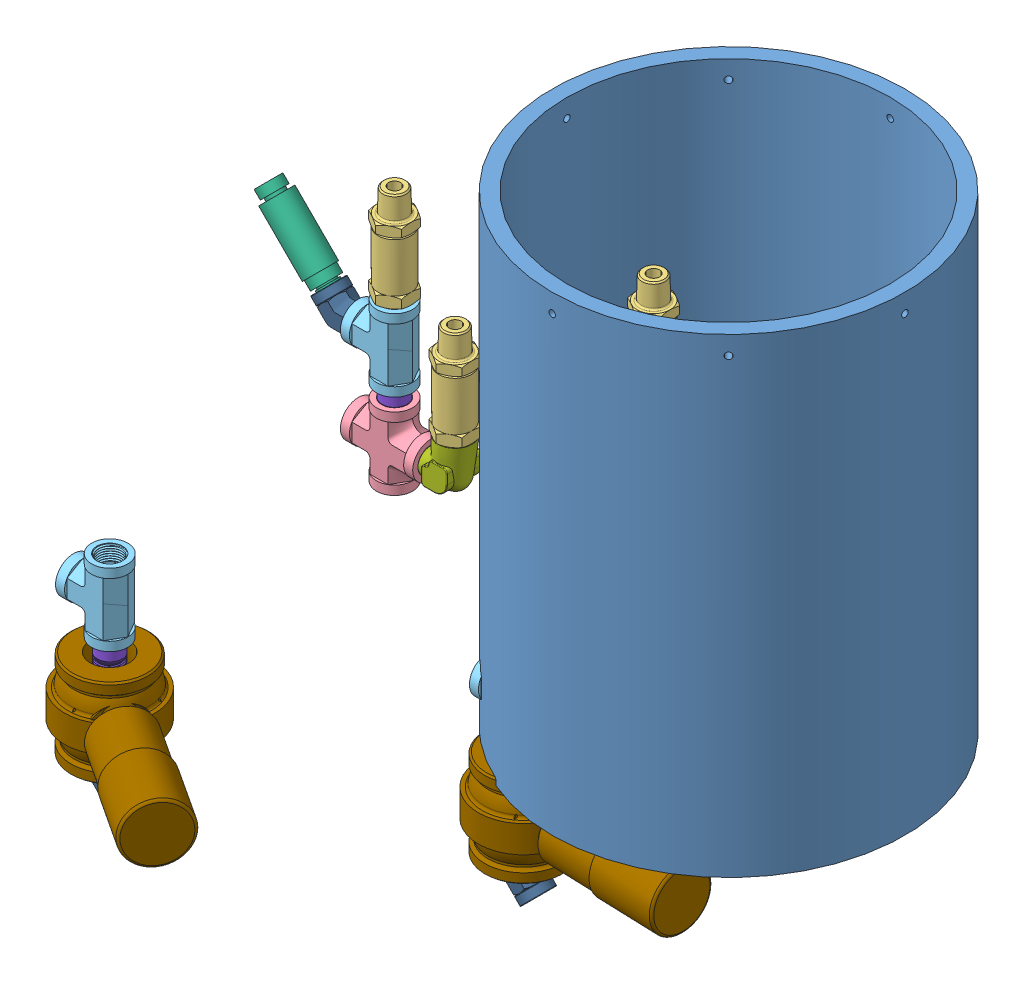
SolidWorks assembly FinCanAssembly, configuration Default. Lengths in mm.
Overall size (594.72 511.85 548.05).
27 component instances, 10 part files, 43 mates.
Components (placement in the parent):
- 000070-R03_FIN_CAN_AF-1: 000070-R03_FIN_CAN_AF [Default] at (23.1188 -196.0045 -17.088) size (304.8 406.4 304.8)
- launch_rail_lugs-1: launch_rail_lugs [Default] at (-92.4476 -84.8795 -132.6545) x (-0.707107 0 0.707107) z (-0.707107 0 -0.707107) size (76.2 32.2 34.22)
- TIN20021-1: TIN20021 [Default] at (7.6331 145.2519 32.2173) x (0 -1 0) z (0 0 1) size (102.11 28.58 33)
- TIN20021-2: TIN20021 [Default] at (-301.1748 13.7827 -52.7696) x (0 -1 0) z (0 0 1) size (102.11 28.58 33)
- 51205K175_EXTREME-PRESSURE 316 SS THREADED PIPE FITTING-1: 51205K175_EXTREME-PRESSURE 316 SS THREADED PIPE FITTING [51205K175] at (7.6331 -24.0899 32.2173) size (63.86 63.86 31.16)
- 51205K175_EXTREME-PRESSURE 316 SS THREADED PIPE FITTING-2: 51205K175_EXTREME-PRESSURE 316 SS THREADED PIPE FITTING [51205K175] at (-301.1748 -155.5591 -52.7696) x (0 -1 0) z (0 0 1) size (63.86 63.86 31.16)
- TIN20021-3: TIN20021 [Default] at (-248.9047 -63.8175 -52.7696) x (0 -1 0) z (0 0 1) size (102.11 28.58 33)
- TIN20021-6: TIN20021 [Default] at (59.9031 67.6517 32.2173) x (0 -1 0) z (0 0 1) size (102.11 28.58 33)
- 51205K245_EXTREME-PRESSURE 316 SS THREADED PIPE FITTING-1: 51205K245_EXTREME-PRESSURE 316 SS THREADED PIPE FITTING [51205K245] at (-301.1748 -81.9753 -52.7696) x (0 1 0) z (0 0 1) size (63.86 47.51 31.16)
- cryo-pducer-temp-1: cryo-pducer-temp [Default] at (-350.8641 -76.2279 -52.7696) x (0.707107 0.707107 0) z (0 0 1) size (25.65 83.82 25.65)
- 51205K245_EXTREME-PRESSURE 316 SS THREADED PIPE FITTING-2: 51205K245_EXTREME-PRESSURE 316 SS THREADED PIPE FITTING [51205K245] at (7.6331 49.4939 32.2173) x (0 1 0) z (0 0 1) size (63.86 47.51 31.16)
- cryo-pducer-temp-2: cryo-pducer-temp [Default] at (-13.4489 49.4939 32.2173) x (0 1 0) z (0 0 1) size (25.65 83.82 25.65)
- 3861T240_MED-PRESSURE ANODIZED ALUM THRD PIPE FITTING-1: 3861T240_MED-PRESSURE ANODIZED ALUM THRD PIPE FITTING [3861T24] at (-248.9047 -125.7935 -52.7696) x (0 0 -1) z (0 1 0) size (30.97 56.51 41.63)
- 44665K173_STANDARD-WALL ALUMINUM THREADED PIPE NIPPLE-1: 44665K173_STANDARD-WALL ALUMINUM THREADED PIPE NIPPLE [44665K173] at (-301.1748 -118.7672 -52.7696) x (1 0 0) z (0 -1 0) size (22.19 22.36 51.97)
- 44665K173_STANDARD-WALL ALUMINUM THREADED PIPE NIPPLE-2: 44665K173_STANDARD-WALL ALUMINUM THREADED PIPE NIPPLE [44665K173] at (7.6331 12.702 32.2173) x (1 0 0) z (0 -1 0) size (22.19 22.36 51.97)
- 3861T240_MED-PRESSURE ANODIZED ALUM THRD PIPE FITTING-2: 3861T240_MED-PRESSURE ANODIZED ALUM THRD PIPE FITTING [3861T24] at (59.9031 5.6757 32.2173) x (0 0 -1) z (0 1 0) size (30.97 56.51 41.63)
- atomatik-1: atomatik [Default] at (58.6758 -183.8479 -36.0375) size (76.23 180.98 78)
- atomatik-2: atomatik [Default] at (-229.8589 -151.0153 264.6801) x (0 -1 0) z (-0.546944 0 0.837169) size (76.23 180.98 78)
- atomatik-3: atomatik [Default] at (-46.8177 -221.3586 90.098) x (0 -1 0) z (-0.035722 0 0.999362) size (76.23 180.98 78)
- atomatik-4: atomatik [Default] at (57.6992 -182.5795 58.8478) size (76.23 180.98 78)
- 51205K245_EXTREME-PRESSURE 316 SS THREADED PIPE FITTING-3: 51205K245_EXTREME-PRESSURE 316 SS THREADED PIPE FITTING [51205K245] at (-46.8177 -148.3929 90.098) x (0 1 0) z (0 0 1) size (63.86 47.51 31.16)
- 44665K173_STANDARD-WALL ALUMINUM THREADED PIPE NIPPLE-3: 44665K173_STANDARD-WALL ALUMINUM THREADED PIPE NIPPLE [44665K173] at (-46.8177 -185.1848 90.098) x (1 0 0) z (0 -1 0) size (22.19 22.36 51.97)
- 51205K245_EXTREME-PRESSURE 316 SS THREADED PIPE FITTING-4: 51205K245_EXTREME-PRESSURE 316 SS THREADED PIPE FITTING [51205K245] at (-229.8589 -78.0496 264.6801) x (0 1 0) z (0 0 1) size (63.86 47.51 31.16)
- 44665K173_STANDARD-WALL ALUMINUM THREADED PIPE NIPPLE-4: 44665K173_STANDARD-WALL ALUMINUM THREADED PIPE NIPPLE [44665K173] at (-229.8589 -114.8415 264.6801) x (1 0 0) z (0 -1 0) size (22.19 22.36 51.97)
- 48805K184_PRECISION EXTREME-PRESSURE 316SS PIPE FITTING-1: 48805K184_PRECISION EXTREME-PRESSURE 316SS PIPE FITTING [48805K184] at (-46.8177 -279.661 90.098) x (0 -1 0) z (0 0 1) size (48.72 34.63 25.66)
- 48805K184_PRECISION EXTREME-PRESSURE 316SS PIPE FITTING-2: 48805K184_PRECISION EXTREME-PRESSURE 316SS PIPE FITTING [48805K184] at (-229.8589 -209.3177 264.6801) x (0 -1 0) z (0 0 1) size (48.72 34.63 25.66)
- 48805K184_PRECISION EXTREME-PRESSURE 316SS PIPE FITTING-3: 48805K184_PRECISION EXTREME-PRESSURE 316SS PIPE FITTING [48805K184] at (-345.1168 -81.9753 -52.7696) x (-1 0 0) z (0 0 -1) size (48.72 34.63 25.66)
Mates (geometry in assembly coordinates):
- Concentric1: concentric aligned: cylinder of 000070-R03_FIN_CAN_AF-1 through (23.1188 210.3955 -17.088) axis (0 -1 0) radius 152.4; cylinder of launch_rail_lugs-1 through (23.1188 -53.1295 -17.088) axis (0 -1 0) radius 152.4
- Concentric2: concentric aligned: cylinder of 000070-R03_FIN_CAN_AF-1 through (-90.7059 -69.0045 -118.7894) axis (-0.707107 0 -0.707107) radius 1.7272; cylinder of launch_rail_lugs-1 through (-98.5093 -69.0045 -126.5928) axis (-0.707107 0 -0.707107) radius 2.4574
- Distance8: distance = 2.54 mm anti-aligned: plane of 51205K245_EXTREME-PRESSURE 316 SS THREADED PIPE FITTING-1 through (-301.1748 -50.7333 -52.7696) normal (0 1 0); plane of TIN20021-2 through (-301.1748 -48.1933 -61.0184) normal (0 -1 0)
- Concentric19: concentric aligned: cone of TIN20021-1 through (7.6331 81.8471 32.2173) axis (0 -1 0); cylinder of 51205K245_EXTREME-PRESSURE 316 SS THREADED PIPE FITTING-2 through (7.6331 67.2739 32.2173) axis (0 -1 0) radius 8.001
- Distance11: distance = 2.54 mm anti-aligned: plane of TIN20021-1 through (7.6331 83.2759 23.9684) normal (0 -1 0); plane of 51205K245_EXTREME-PRESSURE 316 SS THREADED PIPE FITTING-2 through (7.6331 80.7359 32.2173) normal (0 1 0)
- Concentric21: concentric aligned: cylinder of 51205K245_EXTREME-PRESSURE 316 SS THREADED PIPE FITTING-2 through (-10.1469 49.4939 32.2173) axis (1 0 0) radius 8.001; cylinder of cryo-pducer-temp-2 through (-13.4489 49.4939 32.2173) axis (1 0 0) radius 8.89
- Distance12: distance = 2.54 mm anti-aligned: plane of cryo-pducer-temp-2 through (-26.1489 60.9239 32.2173) normal (1 0 0); plane of 51205K245_EXTREME-PRESSURE 316 SS THREADED PIPE FITTING-2 through (-23.6089 49.4939 32.2173) normal (-1 0 0)
- Concentric22: concentric anti-aligned: cylinder of 51205K175_EXTREME-PRESSURE 316 SS THREADED PIPE FITTING-2 through (-301.1748 -173.3391 -52.7696) axis (0 1 0) radius 8.001; cylinder of 44665K173_STANDARD-WALL ALUMINUM THREADED PIPE NIPPLE-1 through (-301.1748 -92.78 -52.7696) axis (0 -1 0) radius 7.8994
- Coincident14: coincident aligned: plane of 51205K175_EXTREME-PRESSURE 316 SS THREADED PIPE FITTING-2 through (-301.1748 -124.3171 -52.7696) normal (0 1 0); circle of 44665K173_STANDARD-WALL ALUMINUM THREADED PIPE NIPPLE-1
- Concentric23: concentric anti-aligned: cylinder of 51205K245_EXTREME-PRESSURE 316 SS THREADED PIPE FITTING-1 through (-301.1748 -113.2173 -52.7696) axis (0 1 0) radius 15.5812; cylinder of 44665K173_STANDARD-WALL ALUMINUM THREADED PIPE NIPPLE-1 through (-301.1748 -113.2173 -52.7696) axis (0 -1 0) radius 10.668
- Coincident15: coincident aligned: plane of 51205K245_EXTREME-PRESSURE 316 SS THREADED PIPE FITTING-1 through (-301.1748 -113.2173 -52.7696) normal (0 -1 0); circle of 44665K173_STANDARD-WALL ALUMINUM THREADED PIPE NIPPLE-1
- Concentric25: concentric aligned: cylinder of 51205K175_EXTREME-PRESSURE 316 SS THREADED PIPE FITTING-1 through (7.6331 7.1521 32.2173) axis (0 -1 0) radius 15.5812; cylinder of 44665K173_STANDARD-WALL ALUMINUM THREADED PIPE NIPPLE-2 through (7.6331 18.2519 32.2173) axis (0 -1 0) radius 10.668
- Coincident16: coincident aligned: plane of 51205K175_EXTREME-PRESSURE 316 SS THREADED PIPE FITTING-1 through (7.6331 7.1521 32.2173) normal (0 1 0); circle of 44665K173_STANDARD-WALL ALUMINUM THREADED PIPE NIPPLE-2
- Concentric26: concentric aligned: cylinder of 51205K245_EXTREME-PRESSURE 316 SS THREADED PIPE FITTING-2 through (7.6331 67.2739 32.2173) axis (0 -1 0) radius 8.001; cylinder of 44665K173_STANDARD-WALL ALUMINUM THREADED PIPE NIPPLE-2 through (7.6331 18.2519 32.2173) axis (0 -1 0) radius 10.668
- Coincident17: coincident aligned: plane of 51205K245_EXTREME-PRESSURE 316 SS THREADED PIPE FITTING-2 through (7.6331 18.2519 32.2173) normal (0 -1 0); circle of 44665K173_STANDARD-WALL ALUMINUM THREADED PIPE NIPPLE-2
- Concentric27: concentric aligned: cylinder of 51205K175_EXTREME-PRESSURE 316 SS THREADED PIPE FITTING-2 through (-283.3948 -155.5591 -52.7696) axis (-1 0 0) radius 8.001; cylinder of 3861T240_MED-PRESSURE ANODIZED ALUM THRD PIPE FITTING-1 through (-266.7641 -155.5591 -52.7696) axis (-1 0 0) radius 6.7469
- Coincident18: coincident anti-aligned: plane of 51205K175_EXTREME-PRESSURE 316 SS THREADED PIPE FITTING-2 through (-269.9328 -155.5591 -52.7696) normal (1 0 0); plane of 3861T240_MED-PRESSURE ANODIZED ALUM THRD PIPE FITTING-1 through (-269.9328 -173.4185 -37.6883) normal (-1 0 0)
- Concentric28: concentric aligned: cone of TIN20021-2 through (-301.1748 -49.622 -52.7696) axis (0 -1 0); cylinder of 51205K245_EXTREME-PRESSURE 316 SS THREADED PIPE FITTING-1 through (-301.1748 -64.1953 -52.7696) axis (0 -1 0) radius 8.001
- Concentric29: concentric aligned: cylinder of 3861T240_MED-PRESSURE ANODIZED ALUM THRD PIPE FITTING-2 through (42.0438 -24.0899 32.2173) axis (-1 0 0) radius 6.7469; cylinder of 51205K175_EXTREME-PRESSURE 316 SS THREADED PIPE FITTING-1 through (25.4131 -24.0899 32.2173) axis (-1 0 0) radius 8.001
- Coincident19: coincident anti-aligned: plane of 51205K175_EXTREME-PRESSURE 316 SS THREADED PIPE FITTING-1 through (38.8751 -24.0899 32.2173) normal (1 0 0); plane of 3861T240_MED-PRESSURE ANODIZED ALUM THRD PIPE FITTING-2 through (38.8751 -41.9493 47.2985) normal (-1 0 0)
- Parallel1: parallel aligned: plane of 51205K175_EXTREME-PRESSURE 316 SS THREADED PIPE FITTING-1 through (19.3489 -35.8057 18.7235) normal (0 0 -1); plane of 3861T240_MED-PRESSURE ANODIZED ALUM THRD PIPE FITTING-2 through (56.7281 -20.9149 17.136) normal (0 0 -1)
- Parallel2: parallel aligned: plane of 51205K175_EXTREME-PRESSURE 316 SS THREADED PIPE FITTING-2 through (-312.8905 -167.2748 -66.2633) normal (0 0 -1); plane of 3861T240_MED-PRESSURE ANODIZED ALUM THRD PIPE FITTING-1 through (-252.0797 -152.3841 -67.8508) normal (0 0 -1)
- Concentric30: concentric aligned: cone of TIN20021-3 through (-248.9047 -127.2222 -52.7696) axis (0 -1 0); circle of 3861T240_MED-PRESSURE ANODIZED ALUM THRD PIPE FITTING-1
- Coincident23: coincident anti-aligned: plane of TIN20021-3 through (-248.9047 -125.7935 -61.0184) normal (0 -1 0); plane of 3861T240_MED-PRESSURE ANODIZED ALUM THRD PIPE FITTING-1 through (-248.9047 -125.7935 -52.7696) normal (0 1 0)
- Concentric31: concentric aligned: cone of TIN20021-6 through (59.9031 4.2469 32.2173) axis (0 -1 0); circle of 3861T240_MED-PRESSURE ANODIZED ALUM THRD PIPE FITTING-2
- Coincident25: coincident anti-aligned: plane of TIN20021-6 through (59.9031 5.6757 23.9684) normal (0 -1 0); plane of 3861T240_MED-PRESSURE ANODIZED ALUM THRD PIPE FITTING-2 through (59.9031 5.6757 32.2173) normal (0 1 0)
- Concentric32: concentric anti-aligned: cylinder of 51205K245_EXTREME-PRESSURE 316 SS THREADED PIPE FITTING-3 through (-46.8177 -179.6349 90.098) axis (0 1 0) radius 15.5812; cylinder of 44665K173_STANDARD-WALL ALUMINUM THREADED PIPE NIPPLE-3 through (-46.8177 -179.6349 90.098) axis (0 -1 0) radius 10.668
- Concentric33: concentric anti-aligned: cylinder of 51205K245_EXTREME-PRESSURE 316 SS THREADED PIPE FITTING-4 through (-229.8589 -109.2916 264.6801) axis (0 1 0) radius 15.5812; cylinder of 44665K173_STANDARD-WALL ALUMINUM THREADED PIPE NIPPLE-4 through (-229.8589 -109.2916 264.6801) axis (0 -1 0) radius 10.668
- Coincident26: coincident aligned: plane of 51205K245_EXTREME-PRESSURE 316 SS THREADED PIPE FITTING-3 through (-46.8177 -179.6349 90.098) normal (0 -1 0); circle of 44665K173_STANDARD-WALL ALUMINUM THREADED PIPE NIPPLE-3
- Coincident27: coincident aligned: plane of 51205K245_EXTREME-PRESSURE 316 SS THREADED PIPE FITTING-4 through (-229.8589 -109.2916 264.6801) normal (0 -1 0); circle of 44665K173_STANDARD-WALL ALUMINUM THREADED PIPE NIPPLE-4
- Concentric34: concentric anti-aligned: cylinder of atomatik-3 through (-46.8177 -245.9894 90.098) axis (0 1 0) radius 16.775; cylinder of 44665K173_STANDARD-WALL ALUMINUM THREADED PIPE NIPPLE-3 through (-46.8177 -179.6349 90.098) axis (0 -1 0) radius 10.668
- Coincident28: coincident aligned: plane of atomatik-3 through (-63.582 -190.7347 89.4988) normal (0 1 0); circle of 44665K173_STANDARD-WALL ALUMINUM THREADED PIPE NIPPLE-3
- Coincident29: coincident aligned: plane of atomatik-2 through (-243.9024 -120.3914 255.5051) normal (0 1 0); circle of 44665K173_STANDARD-WALL ALUMINUM THREADED PIPE NIPPLE-4
- Concentric35: concentric anti-aligned: cylinder of atomatik-2 through (-229.8589 -175.6461 264.6801) axis (0 1 0) radius 16.775; cylinder of 44665K173_STANDARD-WALL ALUMINUM THREADED PIPE NIPPLE-4 through (-229.8589 -109.2916 264.6801) axis (0 -1 0) radius 10.668
- Concentric36: concentric aligned: cylinder of atomatik-2 through (-229.8589 -175.6461 264.6801) axis (0 1 0) radius 16.775; cylinder of 48805K184_PRECISION EXTREME-PRESSURE 316SS PIPE FITTING-2 through (-229.8589 -209.3177 264.6801) axis (0 1 0) radius 5.207
- Concentric38: concentric aligned: cylinder of atomatik-3 through (-46.8177 -245.9894 90.098) axis (0 1 0) radius 16.775; cylinder of 48805K184_PRECISION EXTREME-PRESSURE 316SS PIPE FITTING-1 through (-46.8177 -279.661 90.098) axis (0 1 0) radius 5.207
- Coincident30: coincident anti-aligned: plane of atomatik-3 through (-69.9279 -266.961 89.2719) normal (0 -1 0); plane of 48805K184_PRECISION EXTREME-PRESSURE 316SS PIPE FITTING-1 through (-46.8177 -266.961 112.323) normal (0 1 0)
- Coincident31: coincident anti-aligned: plane of atomatik-2 through (-249.2184 -196.6177 252.032) normal (0 -1 0); plane of 48805K184_PRECISION EXTREME-PRESSURE 316SS PIPE FITTING-2 through (-229.8589 -196.6177 286.9051) normal (0 1 0)
- Concentric39: concentric aligned: cylinder of 51205K245_EXTREME-PRESSURE 316 SS THREADED PIPE FITTING-1 through (-318.9548 -81.9753 -52.7696) axis (1 0 0) radius 8.001; cylinder of 48805K184_PRECISION EXTREME-PRESSURE 316SS PIPE FITTING-3 through (-345.1168 -81.9753 -52.7696) axis (1 0 0) radius 5.207
- Coincident32: coincident anti-aligned: plane of 51205K245_EXTREME-PRESSURE 316 SS THREADED PIPE FITTING-1 through (-332.4168 -81.9753 -52.7696) normal (-1 0 0); plane of 48805K184_PRECISION EXTREME-PRESSURE 316SS PIPE FITTING-3 through (-332.4168 -81.9753 -30.5446) normal (1 0 0)
- Concentric40: concentric aligned: cylinder of cryo-pducer-temp-1 through (-350.8641 -87.7226 -52.7696) axis (0.707107 0.707107 0) radius 8.89; cone of 48805K184_PRECISION EXTREME-PRESSURE 316SS PIPE FITTING-3 through (-350.724 -87.5825 -52.7696) axis (0.707107 0.707107 0)
- Distance13: distance = 2.54 mm anti-aligned: plane of cryo-pducer-temp-1 through (-351.7622 -59.1654 -52.7696) normal (0.707107 -0.707107 0); plane of 48805K184_PRECISION EXTREME-PRESSURE 316SS PIPE FITTING-3 through (-358.0483 -69.0437 -52.7696) normal (-0.707107 0.707107 0)
- Parallel3: parallel aligned: plane of 51205K245_EXTREME-PRESSURE 316 SS THREADED PIPE FITTING-1 through (-301.1748 -81.9753 -39.2758) normal (0 0 1); plane of 48805K184_PRECISION EXTREME-PRESSURE 316SS PIPE FITTING-3 through (-345.1168 -81.9753 -41.6571) normal (0 0 1)
